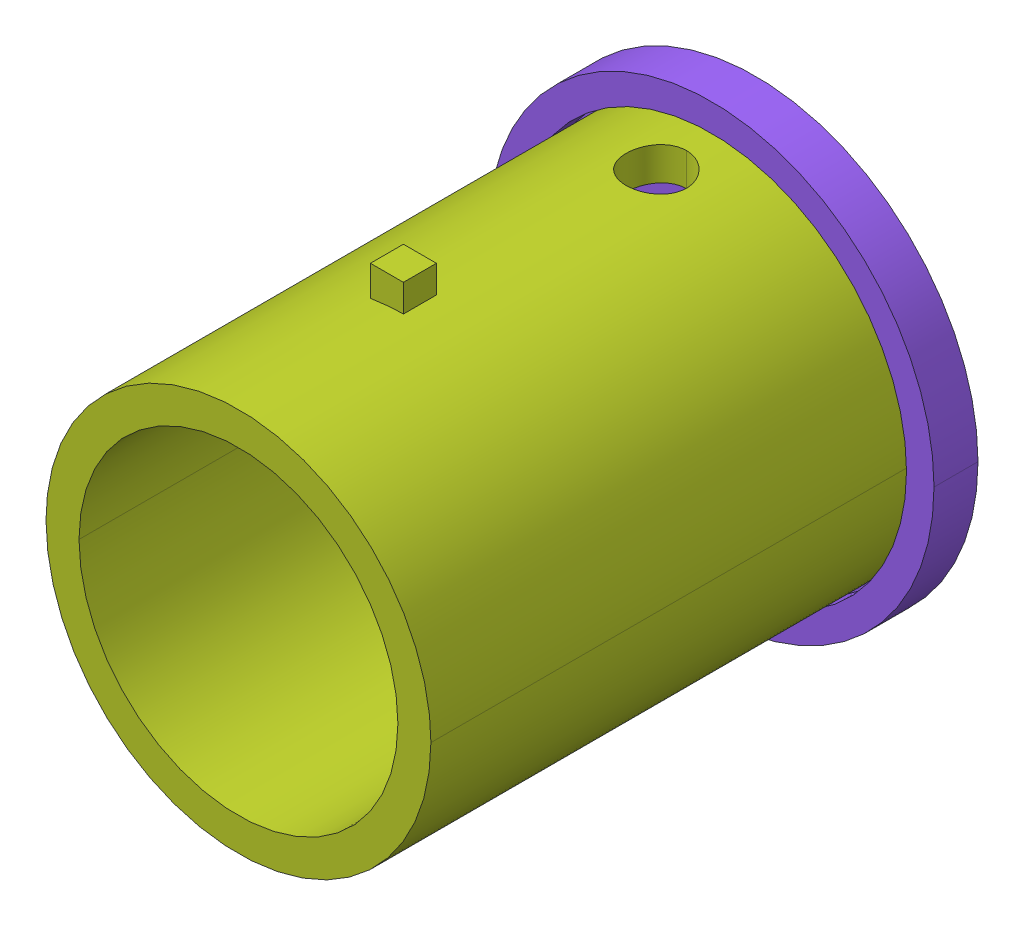
SolidWorks assembly Sensor_full(final), configuration Default. Lengths in mm.
Overall size (40.5 40.5 47).
23 component instances, 8 part files, 0 mates.
Components (placement in the parent):
- Sensor_full(final).STEP-1: Sensor_full(final).STEP [Default] at origin size (40.5 40.5 47)
  - PCB_Sensor (2).step.STEP-1: PCB_Sensor (2).step.STEP [Default] at (29.0403 12.2749 32.6132) x (-1 0 0) z (0 0 -1) size (28 28 15.12)
    - Board.step.STEP-1: Board.step.STEP [Default] at origin size (28 28 0.41)
      - Open CASCADE STEP translator 6.8 1.1.1.step.STEP-1: Open CASCADE STEP translator 6.8 1.1.1.step.STEP [Default] at (0 0 -0.4115) size (28 28 0.41)
    - R7.step.STEP-1: R7.step.STEP [Default] at origin size (2.81 8.17 5.81)
      - Resistor_10K_Ohm_tol1pct_0,25W__07,62.step.STEP-1: Resistor_10K_Ohm_tol1pct_0,25W__07,62.step.STEP [Default] at (25.5486 27.7914 1.8) x (1 0 0) z (0 0 1) size (2.81 8.17 5.81)
    - D1.step.STEP-1: D1.step.STEP [Default] at origin size (5.93 5.41 12.16)
      - LED_5mm_white_TH.step.STEP-1: LED_5mm_white_TH.step.STEP [Default] at (26.6701 17.6531 -2.8115) x (0 1 0) z (0 0 -1) size (5.41 5.93 12.16)
    - R9.step.STEP-1: R9.step.STEP [Default] at origin size (4.88 4.17 9.64)
      - 5044068176.step.STEP-1: 5044068176.step.STEP [Default] at (18.2815 22.1045 -9.0315) size (4.88 4.17 2.29)
        - Extruded.step.STEP-1: Extruded.step.STEP [Default] at origin size (4.88 4.17 2.29)
      - 6007015744.step.STEP-1: 6007015744.step.STEP [Default] at (19.553 22.1045 0.6125) x (-1 0 0) z (0 0 -1) size (0.76 0.76 7.87)
        - Cylinder.step.STEP-1: Cylinder.step.STEP [Default] at origin size (0.76 0.76 7.87)
      - 5044512256.step.STEP-1: 5044512256.step.STEP [Default] at (17.01 22.1045 0.6125) x (1 0 0) z (0 0 -1) size (0.76 0.76 7.87)
        - Cylinder-0.step.STEP-1: Cylinder-0.step.STEP [Default] at origin size (0.76 0.76 7.87)
    - R8.step.STEP-1: R8.step.STEP [Default] at origin size (2.81 8.17 5.81)
      - Resistor_10K_Ohm_tol1pct_0,25W__07,62.step.STEP-1: Resistor_10K_Ohm_tol1pct_0,25W__07,62.step.STEP [Default] at (11.0491 27.6859 1.8) x (1 0 0) z (0 0 1) size (2.81 8.17 5.81)
    - D3.step.STEP-1: D3.step.STEP [Default] at origin size (5.41 5.93 12.16)
      - LED_5mm_white_TH.step.STEP-1: LED_5mm_white_TH.step.STEP [Default] at (18.2881 31.4959 -2.8115) x (1 0 0) z (0 0 -1) size (5.41 5.93 12.16)
    - D2.step.STEP-1: D2.step.STEP [Default] at origin size (5.93 5.41 12.16)
      - LED_5mm_white_TH.step.STEP-1: LED_5mm_white_TH.step.STEP [Default] at (9.9061 17.6531 -2.8115) x (0 1 0) z (0 0 -1) size (5.41 5.93 12.16)
  - sensor_body.STEP-1: sensor_body.STEP [Default] at (10.7593 34.3799 30.3247) size (35 40 45)
  - Sensor_Top.STEP-1: Sensor_Top.STEP [Default] at (10.7593 34.3799 18.3247) size (40.5 40.5 4)
